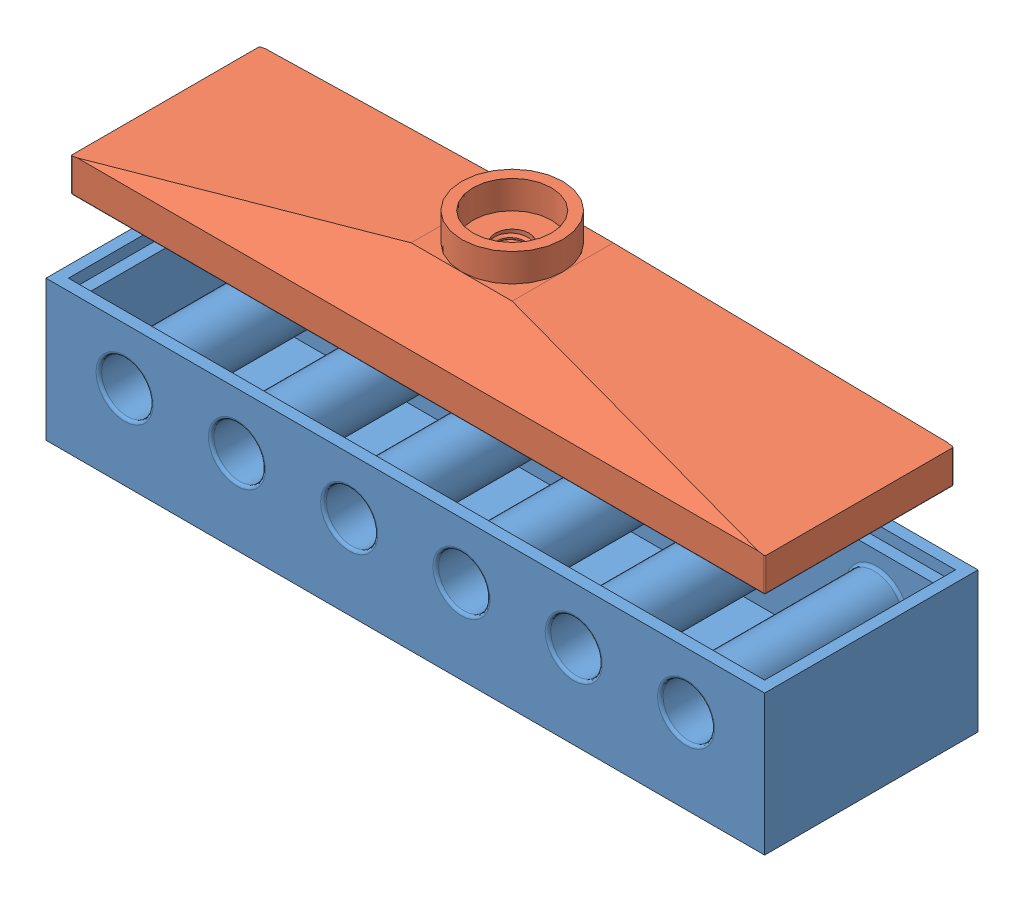
SolidWorks assembly Assem3, configuration Default. Lengths in mm.
Overall size (128 57.98 38).
2 component instances, 2 part files, 0 mates.
Components (placement in the parent):
- 240205_behalter-1: 240205_behalter [Default] at (-75.4796 24.3227 15.8681) size (128 25 38)
- 240205_deckel_new-1: 240205_deckel_new [Default] at (-95.4311 62.3043 15.8778) x (-1 0 0) z (0 0 -1) size (123.6 20 33.6)
